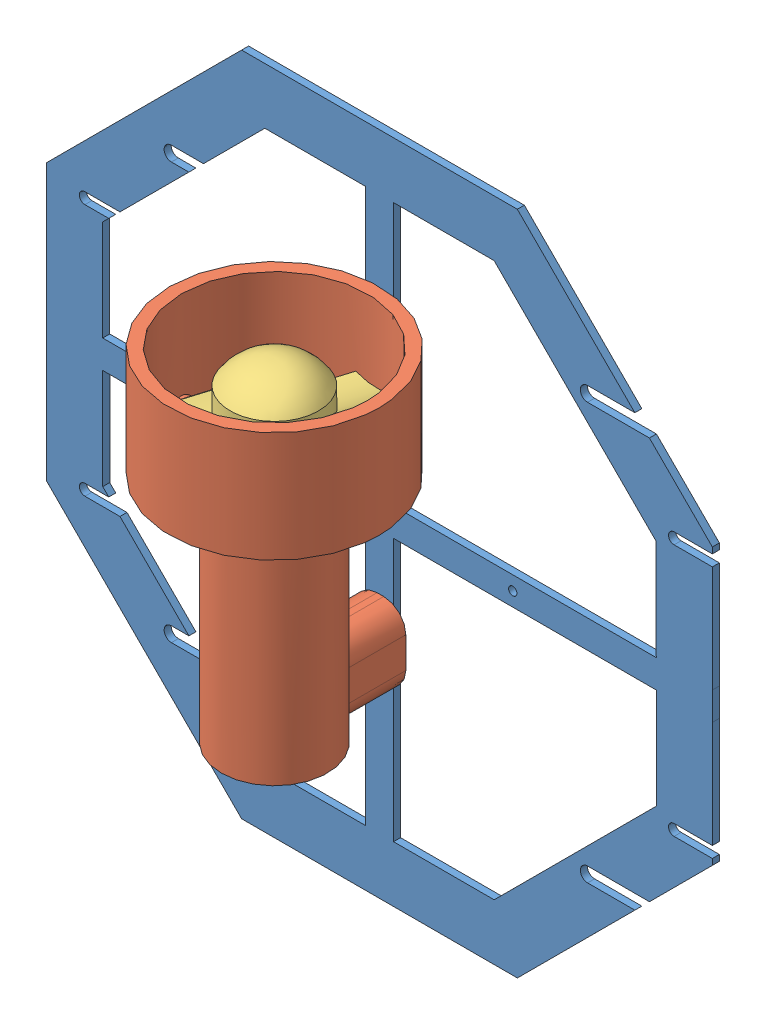
SolidWorks assembly Thruster Octagon, configuration Default. Lengths in mm.
Overall size (301.35 289.37 98.67).
4 component instances, 3 part files, 2 mates.
Components (placement in the parent):
- Thruster Octagon-1: Thruster Octagon [Default] at (-21.0755 20.8016 -4.5986) size (301.35 289.37 3.17)
- propeller-2: propeller [Default] at (23.5208 41.7229 29.3265) x (1 0 0) z (0 -1 0) size (95 95.5 160.94)
  - thruster-1: thruster [Default] at (-44.1774 17.2499 -68.7069) size (95 95.5 160.94)
  - propeller-1: propeller [Default] at (-44.1774 17.2499 -28.7069) x (0.293244 -0.956038 0) z (0 0 -1) size (76 40 35.82)
Mates (geometry in assembly coordinates):
- Concentric1: concentric anti-aligned: circle of Thruster Octagon-1; circle of propeller-2/thruster-1
- Coincident1: coincident anti-aligned: plane of Thruster Octagon-1 through (-171.7413 -129.8772 -1.4236) normal (0 0 1); plane of propeller-2/thruster-1 through (-22.1567 79.3785 -1.4236) normal (0 0 -1)
